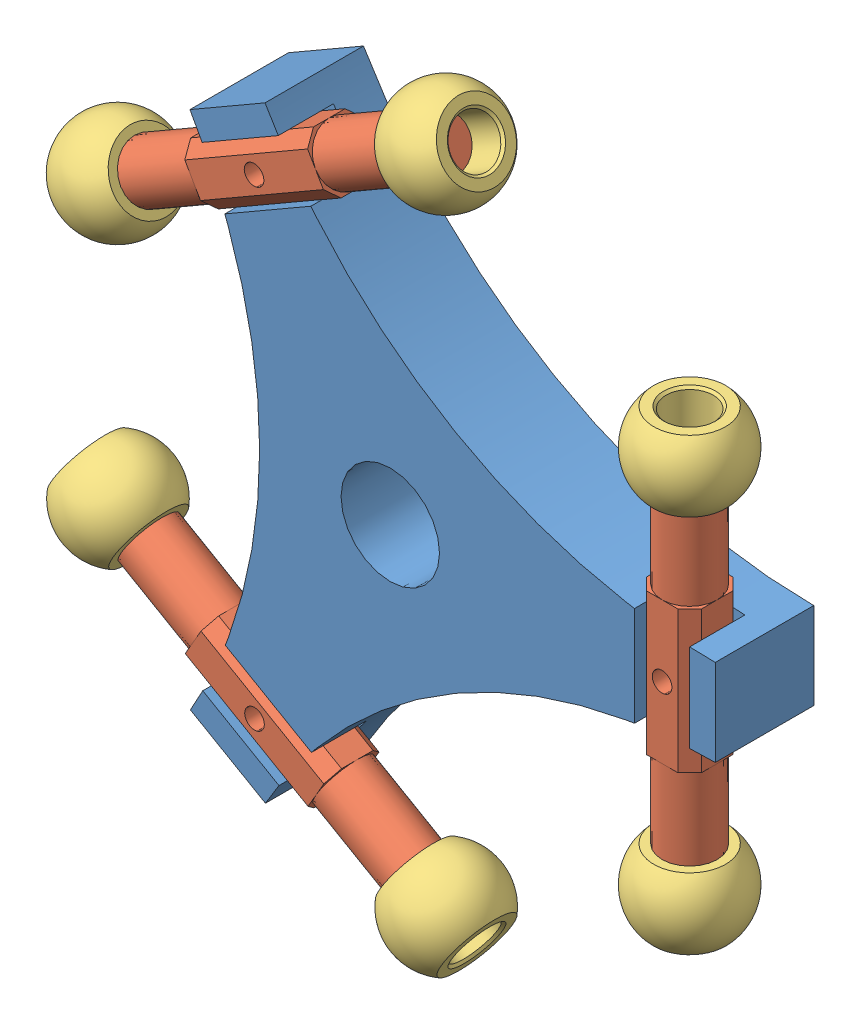
SolidWorks assembly BaseMovilCompleta, configuration Predeterminado. Lengths in mm.
Overall size (86.46 99.4 15.4).
13 component instances, 3 part files, 9 mates.
Components (placement in the parent):
- BaseMovil-1: BaseMovil [Predeterminado] at (2.1349 8.2921 70.7047) size (66.67 76.95 12.5)
- acopleBaseMovilAntebrazo-1: acopleBaseMovilAntebrazo [Predeterminado] at (40.6191 61.9801 72.0388) x (1 0 0) z (0 -1 0) size (12.8 12.8 57.1)
  - Acople-RUniball-BaseMovil-1: Acople-RUniball-BaseMovil [Predeterminado] at (-3.9842 7.6659 29.638) size (7 7 48.1)
  - ball_Uniball-1: ball_Uniball [По умолчанию] at (-3.9842 7.6659 77.738) size (12.8 12.8 9)
  - ball_Uniball-2: ball_Uniball [По умолчанию] at (-3.9842 7.6659 29.638) size (12.8 12.8 9)
- acopleBaseMovilAntebrazo-2: acopleBaseMovilAntebrazo [Predeterminado] at (33.3372 61.5181 72.0388) x (0.5 -0.866025 0) z (-0.866025 -0.5 0) size (12.8 12.8 57.1)
  - Acople-RUniball-BaseMovil-1: Acople-RUniball-BaseMovil [Predeterminado] at (-3.9842 7.6659 29.638) size (7 7 48.1)
  - ball_Uniball-1: ball_Uniball [По умолчанию] at (-3.9842 7.6659 77.738) size (12.8 12.8 9)
  - ball_Uniball-2: ball_Uniball [По умолчанию] at (-3.9842 7.6659 29.638) size (12.8 12.8 9)
- acopleBaseMovilAntebrazo-3: acopleBaseMovilAntebrazo [Predeterminado] at (-59.5962 8.6556 72.0388) x (0.5 0.866025 0) z (0.866025 -0.5 0) size (12.8 12.8 57.1)
  - Acople-RUniball-BaseMovil-1: Acople-RUniball-BaseMovil [Predeterminado] at (-3.9842 7.6659 29.638) size (7 7 48.1)
  - ball_Uniball-1: ball_Uniball [По умолчанию] at (-3.9842 7.6659 77.738) size (12.8 12.8 9)
  - ball_Uniball-2: ball_Uniball [По умолчанию] at (-3.9842 7.6659 29.638) size (12.8 12.8 9)
Mates (geometry in assembly coordinates):
- Coincidente6: coincident anti-aligned: plane of BaseMovil-1 through (2.1349 8.2921 76.2047) normal (0 0 1); plane of acopleBaseMovilAntebrazo-2/Acople-RUniball-BaseMovil-1 through (-21.1943 30.5934 76.2047) normal (0 0 -1)
- Concéntrica1: concentric aligned: circle of BaseMovil-1; circle of acopleBaseMovilAntebrazo-2/Acople-RUniball-BaseMovil-1
- Paralelo2: parallel aligned: line of BaseMovil-1 through (-13.7619 46.7201 83.2047) axis (-0.866025 -0.5 0); line of acopleBaseMovilAntebrazo-2/Acople-RUniball-BaseMovil-1 through (-8.3558 44.3565 83.2047) axis (-0.866025 -0.5 0)
- Coincidente9: coincident anti-aligned: plane of BaseMovil-1 through (2.1349 8.2921 76.2047) normal (0 0 1); plane of acopleBaseMovilAntebrazo-3/Acople-RUniball-BaseMovil-1 through (-5.5489 -23.1078 76.2047) normal (0 0 -1)
- Paralelo3: parallel aligned: line of BaseMovil-1 through (-7.8648 -21.7303 83.2047) axis (-0.866025 0.5 0); line of acopleBaseMovilAntebrazo-3/Acople-RUniball-BaseMovil-1 through (-6.2989 -24.4068 83.2047) axis (-0.866025 0.5 0)
- Concéntrica2: concentric aligned: circle of BaseMovil-1; circle of acopleBaseMovilAntebrazo-3/Acople-RUniball-BaseMovil-1
- Coincidente12: coincident anti-aligned: plane of BaseMovil-1 through (2.1349 8.2921 76.2047) normal (0 0 1); plane of acopleBaseMovilAntebrazo-1/Acople-RUniball-BaseMovil-1 through (40.1349 -0.7079 76.2047) normal (0 0 -1)
- Paralelo4: parallel aligned: line of BaseMovil-1 through (40.1349 2.7064 83.2047) axis (0 1 0); line of acopleBaseMovilAntebrazo-1/Acople-RUniball-BaseMovil-1 through (38.6349 -0.7079 83.2047) axis (0 1 0)
- Concéntrica3: concentric aligned: circle of BaseMovil-1; circle of acopleBaseMovilAntebrazo-1/Acople-RUniball-BaseMovil-1
